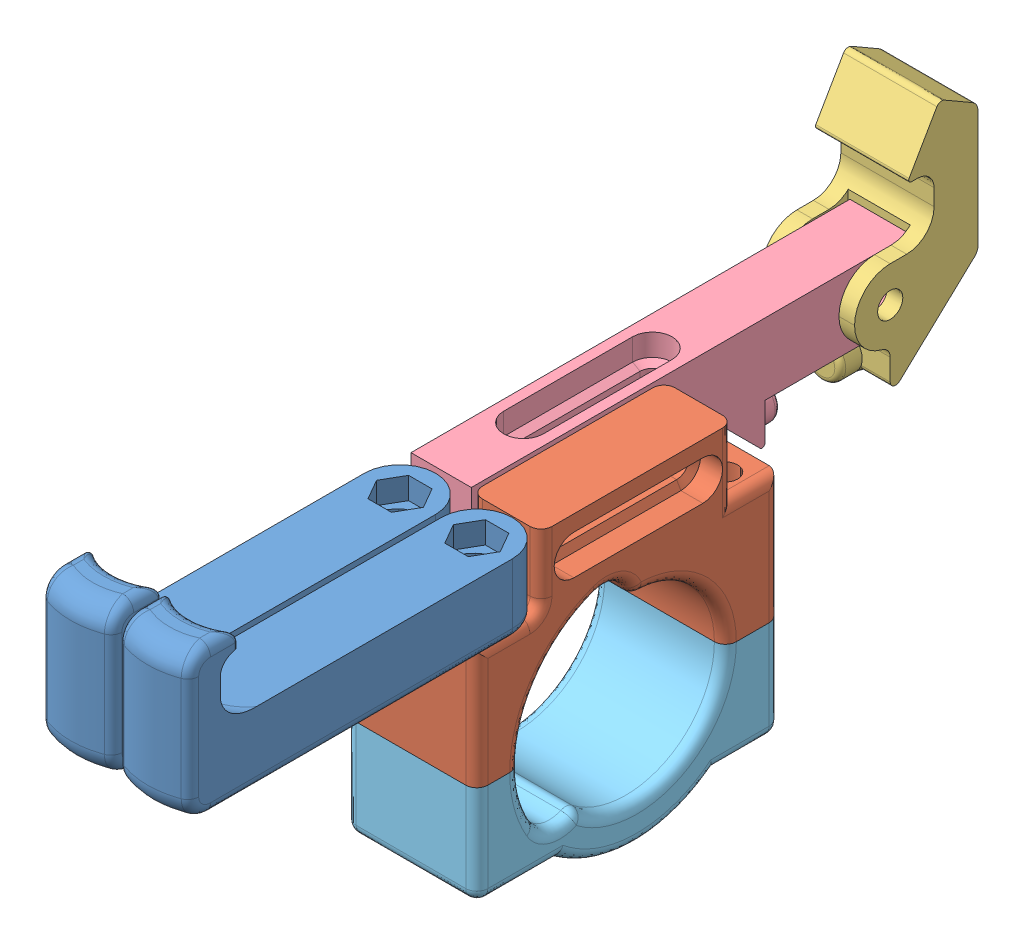
SolidWorks assembly Phone Holder, configuration Standard. Lengths in mm.
Overall size (28.35 79.98 156.2).
6 component instances, 5 part files, 14 mates.
Components (placement in the parent):
- Arm-1: Arm [Standard] at (0.451 -11.9178 99.75) size (13 27.49 66.5)
- Base-1: Base [Standard] at (-18.549 -33.9178 15.6) x (0 0 -1) z (0 -1 0) size (55.3 24 35)
- Lock-1: Lock [Standard] at (-21.399 1.8822 -48.45) x (0 0 -1) z (1 0 0) size (22.5 42.03 17)
- Neck-1: Neck [Standard] at (-18.249 -11.1178 33.05) x (0 0 -1) z (0 -1 0) size (80 11 21.3)
- Arm-2: Arm [Standard] at (-13.549 -11.9178 99.75) size (13 27.49 66.5)
- Counter-1: Counter [Standard] at (-6.549 -33.9178 15.6) x (0 0 1) z (1 0 0) size (55.3 23.15 24)
Mates (geometry in assembly coordinates):
- Konzentrisch1: concentric aligned: cylinder of Arm-1 through (0.451 2.0822 39.75) axis (0 -1 0) radius 2.3; cylinder of Base-1 through (0.451 66.0822 39.75) axis (0 -1 0) radius 2.3
- Deckungsgleich1: coincident anti-aligned: plane of Arm-1 through (0.451 -11.9178 99.75) normal (0 -1 0); plane of Base-1 through (5.451 -11.9178 15.6) normal (0 1 0)
- Konzentrisch2: concentric aligned: cylinder of Base-1 through (-13.549 66.0822 39.75) axis (0 -1 0) radius 2.3; cylinder of Arm-2 through (-13.549 2.0822 39.75) axis (0 -1 0) radius 2.3
- Deckungsgleich2: coincident anti-aligned: plane of Base-1 through (5.451 -11.9178 15.6) normal (0 1 0); plane of Arm-2 through (-13.549 -11.9178 99.75) normal (0 -1 0)
- Deckungsgleich3: coincident anti-aligned: plane of Base-1 through (5.451 -11.1178 15.6) normal (0 1 0); plane of Neck-1 through (-7.249 -11.1178 33.05) normal (0 -1 0)
- Deckungsgleich4: coincident anti-aligned: plane of Base-1 through (-7.249 1.0822 44.75) normal (-1 0 0); plane of Neck-1 through (-7.249 -11.1178 33.05) normal (1 0 0)
- Deckungsgleich5: coincident aligned: plane of Base-1 through (5.451 -33.9178 33.05) normal (0 0 1); plane of Neck-1 through (-7.249 -11.1178 33.05) normal (0 0 1)
- Konzentrisch3: concentric anti-aligned: cylinder of Lock-1 through (-4.399 -4.6178 -40.45) axis (-1 0 0) radius 2.3; circle of Neck-1
- Deckungsgleich7: coincident anti-aligned: plane of Lock-1 through (-7.249 1.8822 -46.95) normal (-1 0 0); plane of Neck-1 through (-7.249 -11.1178 33.05) normal (1 0 0)
- Deckungsgleich8: coincident anti-aligned: plane of Base-1 through (5.451 -33.9178 15.6) normal (0 -1 0); plane of Counter-1 through (5.451 -33.9178 15.6) normal (0 1 0)
- Konzentrisch4: concentric anti-aligned: cylinder of Base-1 through (-13.049 -36.1178 -5.55) axis (0 1 0) radius 2.25; cylinder of Counter-1 through (-13.049 -33.9178 -5.55) axis (0 -1 0) radius 2.25
- Konzentrisch5: concentric aligned: cylinder of Base-1 through (-13.549 66.0822 39.75) axis (0 -1 0) radius 2.3; cylinder of Counter-1 through (-13.549 -33.9178 39.75) axis (0 -1 0) radius 2.25
- Parallel2: parallel anti-aligned: plane of Neck-1 through (-7.249 -11.1178 33.05) normal (0 -1 0); plane of battery-1 through (5.751 -39.7356 -10.7517) normal (0 1 0)
- Deckungsgleich10: coincident aligned: plane of Neck-1 through (-18.249 -11.1178 33.05) normal (-1 0 0); plane of battery-1 through (-18.249 -39.7356 -10.7517) normal (-1 0 0)
